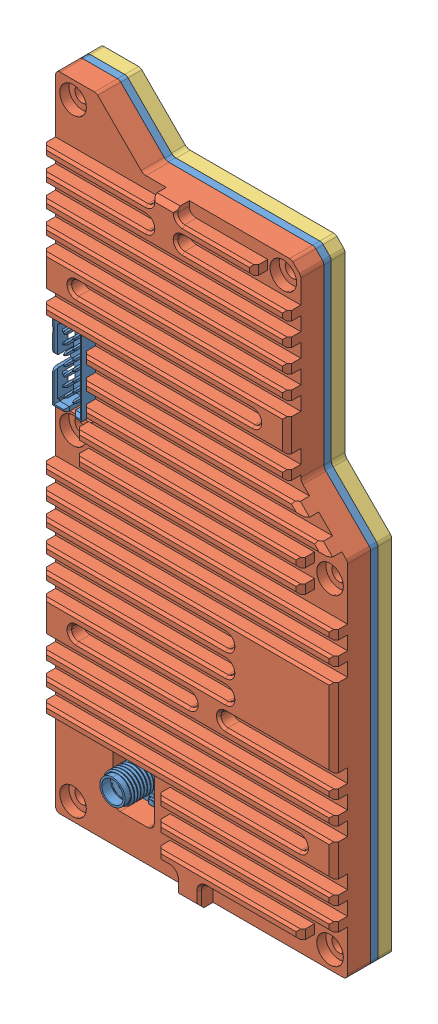
SolidWorks assembly Dboard_IF_RX-7_assembly, configuration Default. Lengths in mm.
Overall size (64.36 139.77 16.66).
12 component instances, 4 part files, 25 mates.
Components (placement in the parent):
- 2m_DBoard_RX-1: 2m_DBoard_RX [Default] at origin size (63.5 139.7 16.66)
- 2m_board_case_top-1: 2m_board_case_top [Default] at (50 50 0) x (1 0 0) z (0 -1 0) size (63.5 8 139.7)
- 2m_board_case_bottom-1: 2m_board_case_bottom [Default] at (50 50 -4.5948) x (1 0 0) z (0 -1 0) size (63.5 3 139.7)
- torx_socket_countersunk_flat_head_M3x10.step-1: torx_socket_countersunk_flat_head_M3x10.step [Default] at (81.75 53.81 -2.9448) x (-0.932434 0.36134 0) z (0 0 -1) size (6 6 10)
- torx_socket_countersunk_flat_head_M3x10.step-2: torx_socket_countersunk_flat_head_M3x10.step [Default] at (53.81 88.74 -2.9448) x (-0.717061 -0.69701 0) z (0 0 -1) size (6 6 10)
- torx_socket_countersunk_flat_head_M3x10.step-3: torx_socket_countersunk_flat_head_M3x10.step [Default] at (53.81 154.77 -2.9448) x (-0.938424 0.345484 0) z (0 0 -1) size (6 6 10)
- torx_socket_countersunk_flat_head_M3x10.step-4: torx_socket_countersunk_flat_head_M3x10.step [Default] at (81.75 53.81 -2.9448) x (-0.932434 0.36134 0) z (0 0 -1) size (6 6 10)
- torx_socket_countersunk_flat_head_M3x10.step-5: torx_socket_countersunk_flat_head_M3x10.step [Default] at (76.67 175.73 -2.9448) x (-0.956943 -0.290275 0) z (0 0 -1) size (6 6 10)
- torx_socket_countersunk_flat_head_M3x10.step-6: torx_socket_countersunk_flat_head_M3x10.step [Default] at (99.53 149.69 -2.9448) x (-0.950696 0.310125 0) z (0 0 -1) size (6 6 10)
- torx_socket_countersunk_flat_head_M3x10.step-7: torx_socket_countersunk_flat_head_M3x10.step [Default] at (109.69 103.34 -2.9448) x (-0.730158 0.683279 0) z (0 0 -1) size (6 6 10)
- torx_socket_countersunk_flat_head_M3x10.step-8: torx_socket_countersunk_flat_head_M3x10.step [Default] at (109.69 74.13 -2.9448) x (-0.986213 0.165482 0) z (0 0 -1) size (6 6 10)
- torx_socket_countersunk_flat_head_M3x10.step-9: torx_socket_countersunk_flat_head_M3x10.step [Default] at (86.07 88.74 -2.9448) x (-0.831379 0.555706 0) z (0 0 -1) size (6 6 10)
Mates (geometry in assembly coordinates):
- Coincident2: coincident: plane of 2m_DBoard_RX-1 through (0 0 0) normal (0 0 1); plane of assembly through (0 0 0) normal (0 0 1)
- Coincident3: coincident: plane of 2m_DBoard_RX-1 through (0 0 0) normal (1 0 0); plane of assembly through (0 0 0) normal (1 0 0)
- Coincident4: coincident: plane of 2m_DBoard_RX-1 through (0 0 0) normal (0 1 0); plane of assembly through (0 0 0) normal (0 1 0)
- Coincident5: coincident: plane of 2m_DBoard_RX-1 through (51 50 0) normal (0 0 1); plane of 2m_board_case_top-1 through (51 51 0) normal (0 0 -1)
- Concentric1: concentric: cylinder of 2m_DBoard_RX-1 through (53.81 53.81 -1.5948) axis (0 0 -1) radius 1.6; cylinder of 2m_board_case_top-1 through (53.81 53.81 8) axis (0 0 1) radius 1.6
- Concentric2: concentric: cylinder of 2m_DBoard_RX-1 through (99.53 175.73 -1.5948) axis (0 0 -1) radius 1.6; cylinder of 2m_board_case_top-1 through (99.53 175.73 8) axis (0 0 1) radius 1.6
- Coincident6: coincident: plane of 2m_DBoard_RX-1 through (51 50 -1.5948) normal (0 0 -1); plane of 2m_board_case_bottom-1 through (51 51 -1.5948) normal (0 0 1)
- Concentric3: concentric: cylinder of 2m_DBoard_RX-1 through (109.69 53.81 -1.5948) axis (0 0 -1) radius 1.6; cylinder of 2m_board_case_bottom-1 through (109.69 53.81 -1.5948) axis (0 0 1) radius 1.6
- Concentric4: concentric: cylinder of 2m_DBoard_RX-1 through (53.81 185.89 -1.5948) axis (0 0 -1) radius 1.6; cylinder of 2m_board_case_bottom-1 through (53.81 185.89 -1.5948) axis (0 0 1) radius 1.6
- Concentric5: concentric: cylinder of 2m_board_case_bottom-1 through (81.75 53.81 -4.5948) axis (0 0 -1) radius 1.7; cylinder of torx_socket_countersunk_flat_head_M3x10.step-1 through (81.75 53.81 5.0552) axis (0 0 -1) radius 1.5
- Coincident7: coincident: cone of 2m_board_case_bottom-1 through (81.75 53.81 -4.5948) axis (0 0 1); cone of torx_socket_countersunk_flat_head_M3x10.step-1 through (81.75 53.81 -4.4448) axis (0 0 1)
- Concentric6: concentric: cylinder of 2m_board_case_bottom-1 through (53.81 88.74 -4.5948) axis (0 0 -1) radius 1.7; cylinder of torx_socket_countersunk_flat_head_M3x10.step-2 through (53.81 88.74 5.0552) axis (0 0 -1) radius 1.5
- Coincident8: coincident: cone of 2m_board_case_bottom-1 through (53.81 88.74 -4.5948) axis (0 0 1); cone of torx_socket_countersunk_flat_head_M3x10.step-2 through (53.81 88.74 -4.4448) axis (0 0 1)
- Concentric7: concentric: cylinder of 2m_board_case_bottom-1 through (53.81 154.77 -4.5948) axis (0 0 -1) radius 1.7; cylinder of torx_socket_countersunk_flat_head_M3x10.step-3 through (53.81 154.77 5.0552) axis (0 0 -1) radius 1.5
- Coincident9: coincident: cone of 2m_board_case_bottom-1 through (53.81 154.77 -4.5948) axis (0 0 1); cone of torx_socket_countersunk_flat_head_M3x10.step-3 through (53.81 154.77 -4.4448) axis (0 0 1)
- Concentric8: concentric: cylinder of 2m_board_case_bottom-1 through (76.67 175.73 -4.5948) axis (0 0 -1) radius 1.7; cylinder of torx_socket_countersunk_flat_head_M3x10.step-5 through (76.67 175.73 5.0552) axis (0 0 -1) radius 1.5
- Coincident10: coincident: cone of 2m_board_case_bottom-1 through (76.67 175.73 -4.5948) axis (0 0 1); cone of torx_socket_countersunk_flat_head_M3x10.step-5 through (76.67 175.73 -4.4448) axis (0 0 1)
- Concentric9: concentric: cylinder of 2m_board_case_bottom-1 through (99.53 149.69 -4.5948) axis (0 0 -1) radius 1.7; cylinder of torx_socket_countersunk_flat_head_M3x10.step-6 through (99.53 149.69 5.0552) axis (0 0 -1) radius 1.5
- Coincident11: coincident: cone of 2m_board_case_bottom-1 through (99.53 149.69 -4.5948) axis (0 0 1); cone of torx_socket_countersunk_flat_head_M3x10.step-6 through (99.53 149.69 -4.4448) axis (0 0 1)
- Concentric10: concentric: cylinder of 2m_board_case_bottom-1 through (109.69 103.34 -4.5948) axis (0 0 -1) radius 1.7; cylinder of torx_socket_countersunk_flat_head_M3x10.step-7 through (109.69 103.34 5.0552) axis (0 0 -1) radius 1.5
- Coincident12: coincident: cone of 2m_board_case_bottom-1 through (109.69 103.34 -4.5948) axis (0 0 1); cone of torx_socket_countersunk_flat_head_M3x10.step-7 through (109.69 103.34 -4.4448) axis (0 0 1)
- Concentric11: concentric: cylinder of 2m_board_case_bottom-1 through (109.69 74.13 -4.5948) axis (0 0 -1) radius 1.7; cylinder of torx_socket_countersunk_flat_head_M3x10.step-8 through (109.69 74.13 5.0552) axis (0 0 -1) radius 1.5
- Coincident13: coincident: cone of 2m_board_case_bottom-1 through (109.69 74.13 -4.5948) axis (0 0 1); cone of torx_socket_countersunk_flat_head_M3x10.step-8 through (109.69 74.13 -4.4448) axis (0 0 1)
- Concentric12: concentric: cylinder of 2m_board_case_bottom-1 through (86.07 88.74 -4.5948) axis (0 0 -1) radius 1.7; cylinder of torx_socket_countersunk_flat_head_M3x10.step-9 through (86.07 88.74 5.0552) axis (0 0 -1) radius 1.5
- Coincident14: coincident: cone of 2m_board_case_bottom-1 through (86.07 88.74 -4.5948) axis (0 0 1); cone of torx_socket_countersunk_flat_head_M3x10.step-9 through (86.07 88.74 -4.4448) axis (0 0 1)
